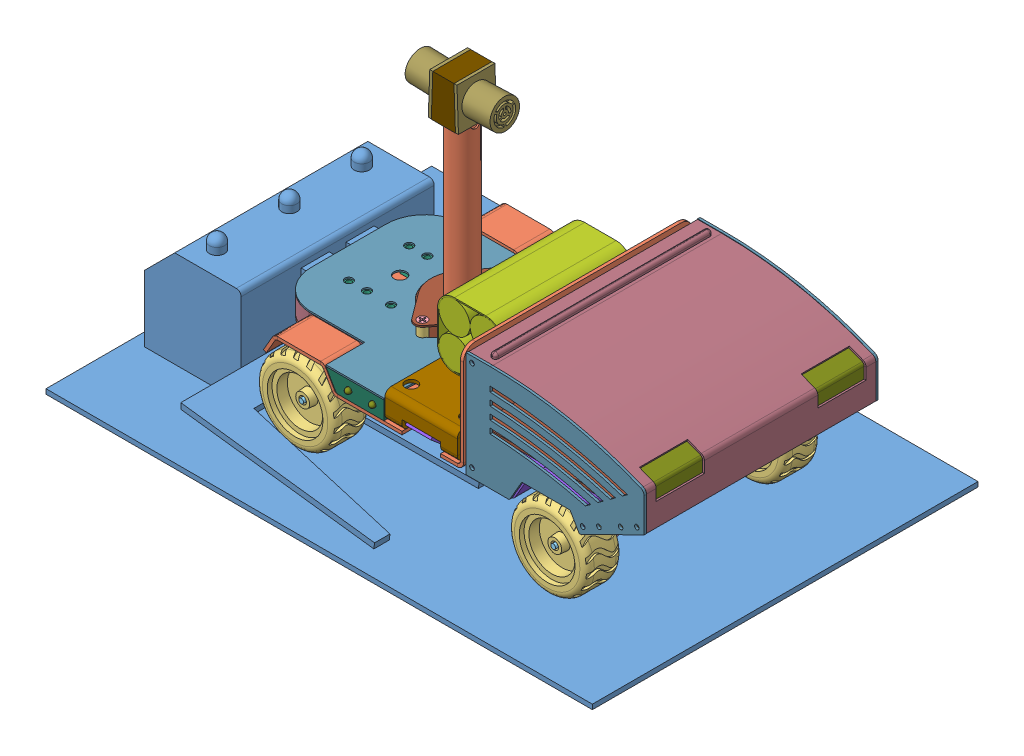
SolidWorks assembly Charging Test Assembly, configuration Default. Lengths in mm.
Overall size (287.48 162.48 202.9).
77 component instances, 37 part files, 11 mates.
Components (placement in the parent):
- Station Shell-1: Station Shell [Default] at (-113.9035 -9.7247 66.6257) size (152.78 58.42 165.1)
- REAR, TOP LEVEL-1: REAR, TOP LEVEL [Default] at (-11.5087 -1.8645 107.5685) x (0 0 1) z (-1 0 0) size (124.43 158.23 120.66)
  - PLATE, REAR-1: PLATE, REAR [Default] at (-42.1312 28.0774 12.7174) size (120.65 55.63 120.66)
  - WHEEL ASSEMBLY-1: WHEEL ASSEMBLY [Default-_flexible1] at (7.6153 26.9792 58.7651) x (0 0 1) z (1 0 0) size (42.46 78.6 70.03) (flexible)
    - Pololu 49x19 Wheel-1: Pololu 49x19 Wheel [Default] at (-19.8703 11.8393 2.4418) size (42.46 42.56 19)
    - Pololu Extended Micro Metal Bracket-1: Pololu Extended Micro Metal Bracket [Default] at (-19.8703 6.8393 -18.4366) size (26.6 22.49 26.04)
    - Pololu 298-1 Motor-1: Pololu 298-1 Motor [Default] at (-19.8703 11.8393 -25.1366) x (0 0 -1) z (0 1 0) size (35.87 12 10)
  - WHEEL ASSEMBLY-2: WHEEL ASSEMBLY [Default-_flexible2] at (-91.8778 26.9792 19.0244) x (0 0 -1) z (-1 0 0) size (42.46 78.6 70.03) (flexible)
    - Pololu 49x19 Wheel-1: Pololu 49x19 Wheel [Default] at (-19.8703 11.8393 2.4418) size (42.46 42.56 19)
    - Pololu Extended Micro Metal Bracket-1: Pololu Extended Micro Metal Bracket [Default] at (-19.8703 6.8393 -18.4366) size (26.6 22.49 26.04)
    - Pololu 298-1 Motor-1: Pololu 298-1 Motor [Default] at (-19.8703 11.8393 -25.1366) x (0 0 -1) z (0 1 0) size (35.87 12 10)
  - Socket Head Cap Screw_AI-1: Socket Head Cap Screw_AI [HX-SHCS 0.086-56x0.4375x0.4375-N] at (-77.6912 31.9128 47.8948) x (0 -1 0) z (-0.381305 0 -0.924449) size (13.3 3.56 3.56)
  - Socket Head Cap Screw_AI-2: Socket Head Cap Screw_AI [HX-SHCS 0.086-56x0.4375x0.4375-N] at (-77.6912 31.9128 29.8948) x (0 -1 0) z (0 0 1) size (13.3 3.56 3.56)
  - Socket Head Cap Screw_AI-3: Socket Head Cap Screw_AI [HX-SHCS 0.086-56x0.4375x0.4375-N] at (-6.5712 31.9128 29.8948) x (0 -1 0) z (0 0 1) size (13.3 3.56 3.56)
  - Socket Head Cap Screw_AI-4: Socket Head Cap Screw_AI [HX-SHCS 0.086-56x0.4375x0.4375-N] at (-6.5712 31.9128 47.8948) x (0 -1 0) z (0 0 1) size (13.3 3.56 3.56)
  - 4000mAh 7.4V Battery Pack-1: 4000mAh 7.4V Battery Pack [Default] at (-42.1312 61.2244 -25.7652) x (0 0 -1) z (1 0 0) size (34.29 34.29 68.58)
  - SENSOR, GP2Y0D810-1: SENSOR, GP2Y0D810 [Default] at (9.9271 36.6454 -23.9419) x (0 0 -1) z (0.766044 0.642788 0) size (28.32 10.54 8.89)
  - SENSOR, GP2Y0D810-2: SENSOR, GP2Y0D810 [Default] at (-94.1896 36.6454 -23.9419) x (0 0 -1) z (0.766044 -0.642788 0) size (28.32 10.54 8.89)
  - Battery Support-1: Battery Support [Default] at (-42.1312 29.7284 -26.0192) size (120.65 27.05 38.1)
  - Mounting Block-1: Mounting Block [Default] at (-42.1312 36.0784 -35.6712) x (-1 0 0) z (0 0 -1) size (25.4 12.7 25.4)
  - PF35T-48-1: PF35T-48 [Default] at (-42.1312 31.7284 12.5888) size (50 29.2 35)
  - MaxSonar EZ1-1: MaxSonar EZ1 [Default] at (-42.1312 140.4691 6.6293) x (-1 0 0) z (0 0.034899 -0.999391) size (19.94 22.1 16.38)
  - MaxSonar EZ1-2: MaxSonar EZ1 [Default] at (-42.1312 140.4691 18.5483) x (1 0 0) z (0 0.034899 0.999391) size (19.94 22.1 16.38)
  - BUMPER, REAR-1: BUMPER, REAR [Default] at (-42.1312 29.7284 53.2288) x (-1 0 0) z (0 0 -1) size (80.01 9.53 54.3)
  - PLATE, REAR COVER-1: PLATE, REAR COVER [Default] at (-42.1312 39.2534 72.2788) size (120.65 0.81 81.14)
  - MOUNTING BLOCK, COLOR SENSOR-1: MOUNTING BLOCK, COLOR SENSOR [Default] at (-97.6937 29.7284 5.6038) size (9.53 9.53 30.46)
  - MOUNTING BLOCK, COLOR SENSOR-2: MOUNTING BLOCK, COLOR SENSOR [Default] at (13.4313 29.7284 5.6038) size (9.53 9.53 30.46)
  - SENSOR, COLOR LED-1: SENSOR, COLOR LED [Default] at (-24.0807 23.782 31.9371) x (0 0 -1) z (-0.409692 -0.912224 0) size (5.83 3.66 3.66)
  - SENSOR, COLOR LED-2: SENSOR, COLOR LED [Default] at (-67.3741 22.996 31.9371) x (0 0 -1) z (-0.202984 -0.979182 0) size (5.83 3.66 3.66)
  - COPPER CONTACT-1: COPPER CONTACT [Default] at (-53.2437 34.4909 64.0238) size (15.88 6.35 4.45)
  - COPPER CONTACT-2: COPPER CONTACT [Default] at (-31.0187 34.4909 64.0238) size (15.88 6.35 4.45)
  - MOUNTING BLOCK, SONAR-1: MOUNTING BLOCK, SONAR [Default] at (-42.1312 140.3989 12.5888) x (-1 0 0) z (0 0 -1) size (19.94 22.23 12.7)
  - SHAFT, SONAR MOUNT-1: SHAFT, SONAR MOUNT [Default] at (-42.1312 52.5784 12.5888) x (-0.538443 0 0.842662) z (-0.842662 0 -0.538443) size (4.76 89.41 4.76)
  - SHAFT, SONAR SUPPORT-1: SHAFT, SONAR SUPPORT [Default] at (-42.1312 46.7284 12.5888) x (0.999987 0 0.005105) z (-0.005105 0 0.999987) size (14.22 82.87 14.22)
  - SHAFT, STEPPER SUPPORT-1: SHAFT, STEPPER SUPPORT [Default] at (-63.1312 29.6724 12.5888) size (4.76 16.26 4.76)
  - SHAFT, STEPPER SUPPORT-2: SHAFT, STEPPER SUPPORT [Default] at (-21.1312 29.6724 12.5888) x (0.987866 0 -0.155311) z (0.155311 0 0.987866) size (4.76 16.26 4.76)
  - Flat Head 100 Screw_AI-2: Flat Head 100 Screw_AI [CR-FHM1 0.112-40x0.25x0.25-N] at (-63.1312 46.7284 12.5888) x (0 -1 0) z (0 0 1) size (6.35 4.85 4.85)
  - Flat Head 100 Screw_AI-3: Flat Head 100 Screw_AI [CR-FHM1 0.112-40x0.25x0.25-N] at (-21.1312 46.7284 12.5888) x (0 -1 0) z (0 0 1) size (6.35 4.85 4.85)
  - CONNECTOR, MOLEX 6 PIN-1: CONNECTOR, MOLEX 6 PIN [Default] at (-80.2263 37.7912 12.5433) size (10.34 13.8 9.75)
  - SENSOR, COLOR LED-3: SENSOR, COLOR LED [Default] at (-64.0196 42.7147 3.5765) x (1 0 0) z (0 0.700538 -0.713616) size (5.83 3.66 3.66)
  - SENSOR, COLOR LED-4: SENSOR, COLOR LED [Default] at (-64.0196 42.7147 -9.1235) x (1 0 0) z (0 0.700538 -0.713616) size (5.83 3.66 3.66)
  - SENSOR, COLOR LED-5: SENSOR, COLOR LED [Default] at (-20.2429 42.7147 20.3311) x (-1 0 0) z (0 0.700538 0.713616) size (5.83 3.66 3.66)
  - SENSOR, COLOR LED-6: SENSOR, COLOR LED [Default] at (-20.2429 42.7147 7.6311) x (-1 0 0) z (0 0.700538 0.713616) size (5.83 3.66 3.66)
  - MOUNTING BLOCK, REAR-1: MOUNTING BLOCK, REAR [Default] at (-58.0062 34.4909 31.0038) size (9.53 9.53 28.57)
  - MOUNTING BLOCK, REAR-2: MOUNTING BLOCK, REAR [Default] at (-26.2562 34.4909 31.0038) size (9.53 9.53 28.57)
  - SW3dPS-Sliderswitch-1: SW3dPS-Sliderswitch [Standard] at (-81.1109 44.0794 -21.7288) size (7.4 16 23.2)
- FRONT, TOP LEVEL-1: FRONT, TOP LEVEL [Default] at (64.5283 -20.2944 141.9007) x (0 0 1) z (-1 0 0) size (123.38 92.14 123.57)
  - PLATE, FRONT-1: PLATE, FRONT [Default] at (-76.4634 46.5072 -32.0242) size (120.65 12.1 60.8)
  - WHEEL ASSEMBLY-1: WHEEL ASSEMBLY [Default-_flexible3] at (-26.7168 45.4091 2.1802) x (0 0 1) z (1 0 0) size (42.46 78.6 70.03) (flexible)
    - Pololu 49x19 Wheel-1: Pololu 49x19 Wheel [Default] at (-19.8703 11.8393 2.4418) size (42.46 42.56 19)
    - Pololu Extended Micro Metal Bracket-1: Pololu Extended Micro Metal Bracket [Default] at (-19.8703 6.8393 -18.4366) size (26.6 22.49 26.04)
    - Pololu 298-1 Motor-1: Pololu 298-1 Motor [Default] at (-19.8703 11.8393 -25.1366) x (0 0 -1) z (0 1 0) size (35.87 12 10)
  - WHEEL ASSEMBLY-2: WHEEL ASSEMBLY [Default-_flexible4] at (-126.21 45.4091 -37.5605) x (0 0 -1) z (-1 0 0) size (42.46 78.6 70.03) (flexible)
    - Pololu 49x19 Wheel-1: Pololu 49x19 Wheel [Default] at (-19.8703 11.8393 2.4418) size (42.46 42.56 19)
    - Pololu Extended Micro Metal Bracket-1: Pololu Extended Micro Metal Bracket [Default] at (-19.8703 6.8393 -18.4366) size (26.6 22.49 26.04)
    - Pololu 298-1 Motor-1: Pololu 298-1 Motor [Default] at (-19.8703 11.8393 -25.1366) x (0 0 -1) z (0 1 0) size (35.87 12 10)
  - Socket Head Cap Screw_AI-1: Socket Head Cap Screw_AI [HX-SHCS 0.086-56x0.4375x0.4375-N] at (-112.0234 50.3426 -8.6902) x (0 -1 0) z (0.989468 0 0.144748) size (13.3 3.56 3.56)
  - Socket Head Cap Screw_AI-3: Socket Head Cap Screw_AI [HX-SHCS 0.086-56x0.4375x0.4375-N] at (-40.9034 50.3426 -8.6902) x (0 -1 0) z (0.700957 0 0.713204) size (13.3 3.56 3.56)
  - SENSOR, GP2Y0D810-2: SENSOR, GP2Y0D810 [Default] at (-76.7491 52.0249 -21.9932) x (1 0 0) z (0 -0.642788 0.766044) size (28.32 10.54 8.89)
  - BUMPER, FRONT-1: BUMPER, FRONT [Default] at (-76.4634 36.9822 -30.9902) x (-1 0 0) z (0 0 -1) size (69.85 9.53 6.35)
  - Mounting Block-1: Mounting Block [Default] at (-76.4634 54.5082 12.4258) size (25.4 12.7 25.4)
  - Socket Head Shoulder Screw2_AI-1: Socket Head Shoulder Screw2_AI [SHSSCREW 0.25x1.5-N] at (-76.4634 54.5082 2.5706) x (0 0 1) z (-0.728467 -0.685081 0) size (52.4 9.53 9.53)
  - Socket Head Cap Screw_AI-5: Socket Head Cap Screw_AI [HX-SHCS 0.086-56x0.4375x0.4375-N] at (-40.9034 51.2773 -26.6902) x (0 -1 0) z (-0.957829 0 -0.287339) size (13.3 3.56 3.56)
  - Socket Head Cap Screw_AI-6: Socket Head Cap Screw_AI [HX-SHCS 0.086-56x0.4375x0.4375-N] at (-112.0234 51.2773 -26.6902) x (0 -1 0) z (-0.957829 0 -0.287339) size (13.3 3.56 3.56)
  - PCB, MAIN-1: PCB, MAIN [Default] at (-76.4634 67.2082 -21.6044) size (114.3 6.68 88.9)
  - PLATE, FRONT BUMPER-1: PLATE, FRONT BUMPER [Default] at (-76.4634 48.9202 -22.7941) size (120.65 17.91 44.79)
  - COVER, FRONT-1: COVER, FRONT [Default] at (-76.4634 65.9445 25.1258) size (120.65 38.48 93.73)
  - PLATE, FRONT SIDE-1: PLATE, FRONT SIDE [Default] at (-16.1384 46.5072 25.1258) x (0 0 -1) z (1 0 0) size (93.73 55.63 1.27)
  - SW3dPS-USB_mini_B-1: SW3dPS-USB_mini_B [По умолчанию] at (-54.9865 68.8084 -58.5669) x (-1 0 0) z (0 0 -1) size (10.7 4.95 9.2)
  - HEADLIGHT COVER, FRONT-1: HEADLIGHT COVER, FRONT [Default] at (-103.1334 74.8345 -67.5842) x (-1 0 0) z (0 0 -1) size (31.75 14.4 11.68)
  - HEADLIGHT COVER, FRONT-2: HEADLIGHT COVER, FRONT [Default] at (-18.0434 74.8345 -67.5842) x (-1 0 0) z (0 0 -1) size (31.75 14.4 11.68)
  - PLATE, FRONT SIDE-2: PLATE, FRONT SIDE [Default] at (-138.0584 46.5072 25.1258) x (0 0 -1) z (1 0 0) size (93.73 55.63 1.27)
  - STRUT, FRONT SIDE-1: STRUT, FRONT SIDE [Default] at (-76.4634 98.9582 21.9508) size (120.65 3.17 6.35)
- purple LED-1: purple LED [Default] at (-113.9035 4.2262 116.465) x (0 -1 0) z (0 0 1) size (5.83 3.66 3.66)
- purple LED-2: purple LED [Default] at (-113.9035 4.2262 78.365) x (0 -1 0) z (0 0 1) size (5.83 3.66 3.66)
- purple LED-3: purple LED [Default] at (-113.9035 4.2262 40.265) x (0 -1 0) z (0 0 1) size (5.83 3.66 3.66)
- Ground-1: Ground [Default] at (-30.2243 -12.2647 76.1359) size (287.48 2.54 202.9)
Mates (geometry in assembly coordinates):
- Parallel1: parallel anti-aligned: plane of REAR, TOP LEVEL-1/PLATE, REAR-1 through (-30.4475 26.2128 25.4323) normal (0 -1 0); plane of Ground-1 through (-146.1826 -9.7247 -40.4925) normal (0 1 0)
- Concentric2: concentric anti-aligned: cylinder of REAR, TOP LEVEL-1/Mounting Block-1; cylinder of FRONT, TOP LEVEL-1/Socket Head Shoulder Screw2_AI-1
- Distance2: distance = 2.54 mm anti-aligned: plane of REAR, TOP LEVEL-1/Mounting Block-1 through (36.8625 40.5638 52.7373) normal (1 0 0); plane of FRONT, TOP LEVEL-1/Mounting Block-1 through (39.4025 40.5638 78.1373) normal (-1 0 0)
- Parallel2: parallel aligned: plane of REAR, TOP LEVEL-1/PLATE, REAR-1 through (-30.4475 26.2128 25.4323) normal (0 -1 0); plane of FRONT, TOP LEVEL-1/PLATE, FRONT-1 through (62.2625 26.2128 25.4323) normal (0 -1 0)
- Coincident4: coincident aligned: plane of purple LED-1 through (-115.7542 38.7258 106.5765) normal (0 -1 0); plane of purple LED-2 through (-115.7542 38.7258 68.4765) normal (0 -1 0)
- Coincident5: coincident aligned: plane of purple LED-2 through (-115.7542 38.7258 68.4765) normal (0 -1 0); plane of purple LED-3 through (-115.7542 38.7258 30.3765) normal (0 -1 0)
- Coincident6: coincident anti-aligned: plane of Station Shell-1 through (-139.3035 39.4878 117.4257) normal (0 -1 0); plane of purple LED-2 through (-115.7542 39.4878 64.775) normal (0 1 0)
- Concentric3: concentric anti-aligned: cylinder of Station Shell-1; cylinder of purple LED-3
- Concentric4: concentric anti-aligned: cylinder of Station Shell-1; cylinder of purple LED-2
- Concentric5: concentric anti-aligned: cylinder of Station Shell-1; cylinder of purple LED-1
- Coincident7: coincident anti-aligned: plane of Ground-1 through (-146.1826 -9.7247 -40.4925) normal (0 1 0); plane of Station Shell-1 through (-139.3035 -9.7247 117.4257) normal (0 -1 0)
